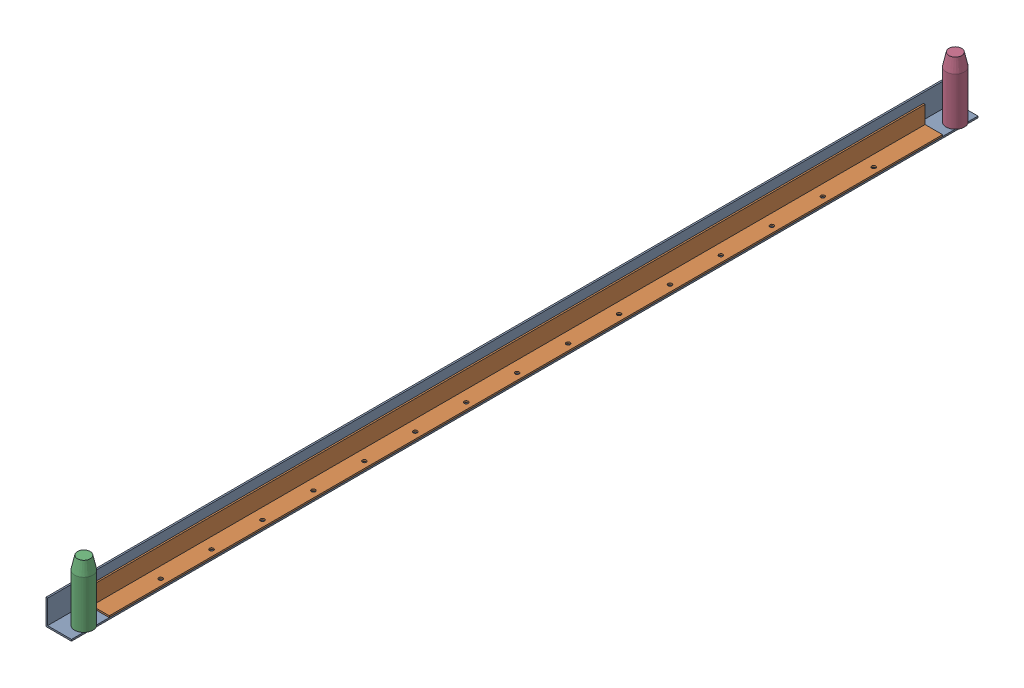
SolidWorks assembly FE-00007_ASM, configuration Default. Lengths in mm.
Overall size (56.36 123.83 1808.16).
4 component instances, 3 part files, 0 mates.
Components (placement in the parent):
- FE-00007-01_AF0-1: FE-00007-01_AF0 [Default] at origin size (50.8 50.8 1808.16)
- FE-00007-02_AF0-1: FE-00007-02_AF0 [Default] at (12.7 3.175 -2.3813) size (38.1 38.1 1662.11)
- FE-00007-03-1: FE-00007-03 [Default] at (38.1 123.825 866.775) x (-1 0 0) z (0 1 0) size (36.51 36.51 120.65)
- FE-00007-03-2: FE-00007-03 [Default] at (38.1 123.825 -871.5375) x (-1 0 0) z (0 1 0) size (36.51 36.51 120.65)
